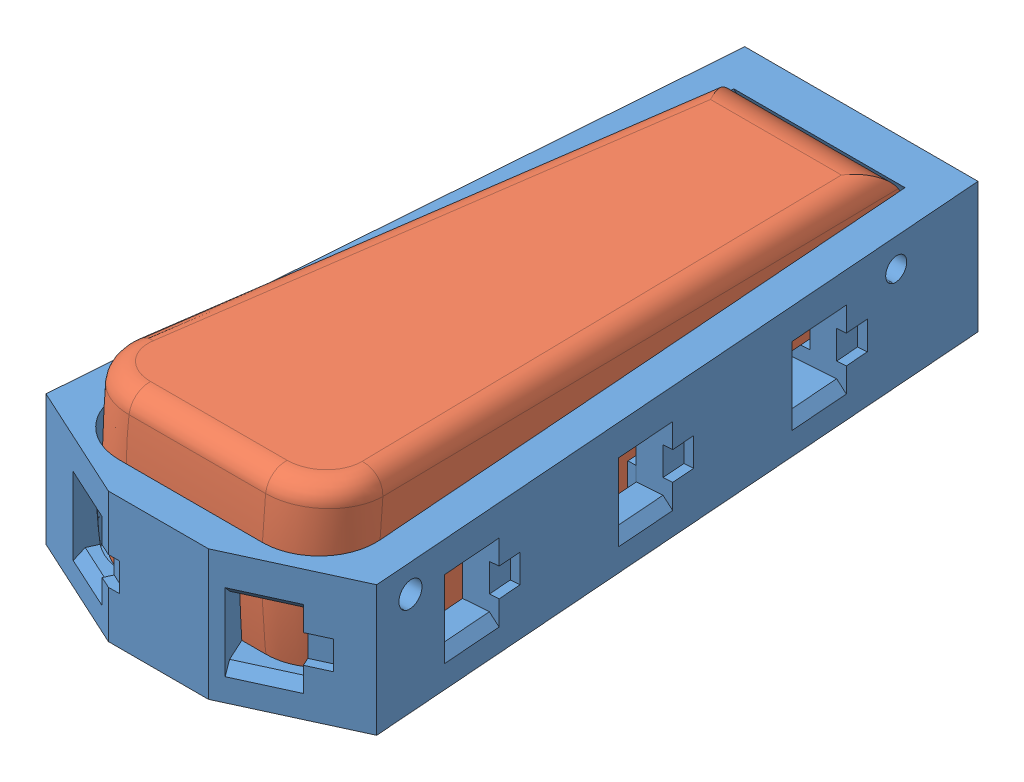
SolidWorks assembly SwitschAssembly, configuration Default. Lengths in mm.
Overall size (29.17 17.83 62).
2 component instances, 2 part files, 2 mates.
Components (placement in the parent):
- SwitchHousing-1: SwitchHousing [Default] at (-144.5731 34.074 64.2085) size (29.17 13.5 62)
- Part2^SwitschAssembly-1: Part2^SwitschAssembly [Default] at (-144.5731 29.574 41.0085) x (0 0.059044 0.998255) z (-1 0 0) size (55.8 14.56 22.57) (virtual)
Mates (geometry in assembly coordinates):
- Concentric1: concentric: cylinder of assembly; cylinder of assembly; cylinder of SwitchHousing-1 through (-159.2731 29.574 41.0085) axis (1 0 0) radius 1; cylinder of Part2^SwitschAssembly-1 through (-155.9731 29.574 41.0085) axis (1 0 0) radius 1.05
- Coincident11: coincident: plane of assembly; plane of assembly; plane of SwitchHousing-1 through (-144.5731 34.074 64.2085) normal (1 0 0); plane of Part2^SwitschAssembly-1 through (-144.5731 29.574 41.0085) normal (-1 0 0)
